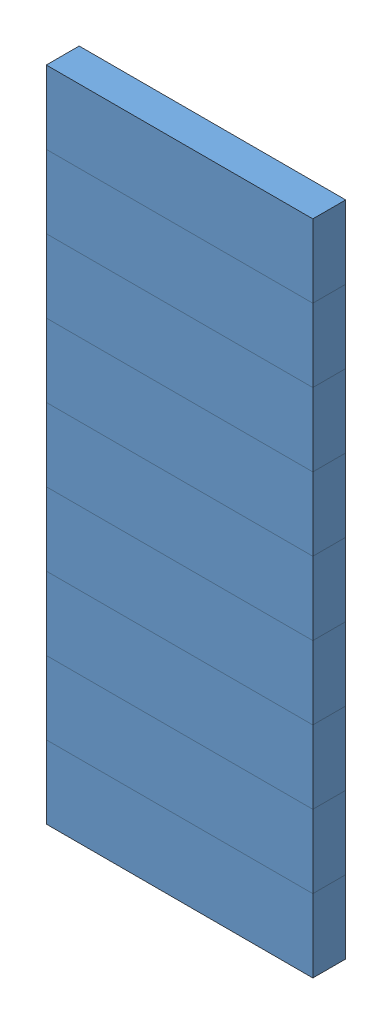
SolidWorks assembly Assem1, configuration Default. Lengths in mm.
Overall size (1.5 3.7 0.18).
9 component instances, 1 part files, 16 mates.
Components (placement in the parent):
- segment-1: segment [Default] at (-0.2715 0.8552 1.5409) size (1.5 0.41 0.18)
- segment-2: segment [Default] at (-0.2715 1.2663 1.5409) size (1.5 0.41 0.18)
- segment-3: segment [Default] at (-0.2715 1.6774 1.5409) size (1.5 0.41 0.18)
- segment-4: segment [Default] at (-0.2715 2.0885 1.5409) size (1.5 0.41 0.18)
- segment-5: segment [Default] at (-0.2715 2.4997 1.5409) size (1.5 0.41 0.18)
- segment-6: segment [Default] at (-0.2715 2.9108 1.5409) size (1.5 0.41 0.18)
- segment-7: segment [Default] at (-0.2715 3.3219 1.5409) size (1.5 0.41 0.18)
- segment-8: segment [Default] at (-0.2715 3.733 1.5409) size (1.5 0.41 0.18)
- segment-9: segment [Default] at (-0.2715 4.1441 1.5409) size (1.5 0.41 0.18)
Mates (geometry in assembly coordinates):
- Coincident5: coincident aligned: line of segment-1 through (-0.2715 1.2663 1.7259) axis (1 0 0); line of segment-2 through (-0.2715 1.2663 1.7259) axis (1 0 0)
- Coincident6: coincident aligned: line of segment-1 through (1.2285 1.2663 1.7259) axis (0 0 -1); line of segment-2 through (1.2285 1.2663 1.7259) axis (0 0 -1)
- Coincident7: coincident aligned: line of segment-2 through (1.2285 1.6774 1.7259) axis (0 0 -1); line of segment-3 through (1.2285 1.6774 1.7259) axis (0 0 -1)
- Coincident8: coincident aligned: line of segment-2 through (-0.2715 1.6774 1.7259) axis (1 0 0); line of segment-3 through (-0.2715 1.6774 1.7259) axis (1 0 0)
- Coincident9: coincident aligned: line of segment-3 through (1.2285 2.0885 1.7259) axis (0 0 -1); line of segment-4 through (1.2285 2.0885 1.7259) axis (0 0 -1)
- Coincident10: coincident aligned: line of segment-3 through (-0.2715 2.0885 1.7259) axis (1 0 0); line of segment-4 through (-0.2715 2.0885 1.7259) axis (1 0 0)
- Coincident11: coincident aligned: line of segment-4 through (1.2285 2.4997 1.7259) axis (0 0 -1); line of segment-5 through (1.2285 2.4997 1.7259) axis (0 0 -1)
- Coincident12: coincident aligned: line of segment-4 through (-0.2715 2.4997 1.7259) axis (1 0 0); line of segment-5 through (-0.2715 2.4997 1.7259) axis (1 0 0)
- Coincident13: coincident aligned: line of segment-5 through (1.2285 2.9108 1.7259) axis (0 0 -1); line of segment-6 through (1.2285 2.9108 1.7259) axis (0 0 -1)
- Coincident14: coincident aligned: line of segment-5 through (-0.2715 2.9108 1.7259) axis (1 0 0); line of segment-6 through (-0.2715 2.9108 1.7259) axis (1 0 0)
- Coincident15: coincident: line of segment-7 through (1.2285 3.3219 1.7259) axis (0 0 -1); line of segment-6 through (1.2285 3.3219 1.7259) axis (0 0 -1)
- Coincident16: coincident aligned: line of segment-6 through (-0.2715 3.3219 1.7259) axis (1 0 0); line of segment-7 through (-0.2715 3.3219 1.7259) axis (1 0 0)
- Coincident17: coincident: line of segment-7 through (1.2285 3.733 1.7259) axis (0 0 -1); line of segment-8 through (1.2285 3.733 1.7259) axis (0 0 -1)
- Coincident18: coincident aligned: line of segment-7 through (-0.2715 3.733 1.7259) axis (1 0 0); line of segment-8 through (-0.2715 3.733 1.7259) axis (1 0 0)
- Coincident19: coincident: line of segment-8 through (1.2285 4.1441 1.7259) axis (0 0 -1); line of segment-9 through (1.2285 4.1441 1.7259) axis (0 0 -1)
- Coincident20: coincident aligned: line of segment-8 through (-0.2715 4.1441 1.7259) axis (1 0 0); line of segment-9 through (-0.2715 4.1441 1.7259) axis (1 0 0)
